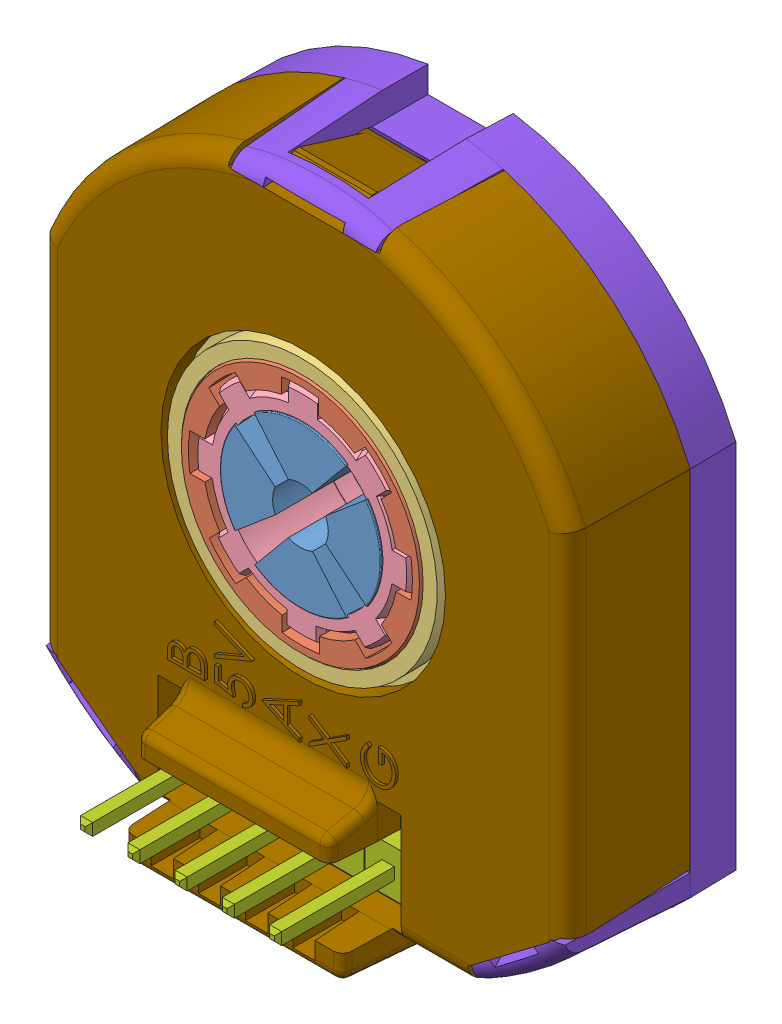
SolidWorks assembly CUI_DEVICES_CUI_DEVICES_AMT103-D0048-I3000-S, configuration Default. Lengths in mm.
Overall size (36.33 37.04 14.49).
9 component instances, 9 part files, 0 mates.
Components (placement in the parent):
- CUI_DEVICES_AMT-Sleeve-REV-D(3 mm)-1: CUI_DEVICES_AMT-Sleeve-REV-D(3 mm) [Default] at (0 0 -2.42) x (0.999996 0.002864 0) z (0 0 1) size (10.79 10.79 7.8)
- CUI_DEVICES_AMT-Hub-Top-REV-D1-1: CUI_DEVICES_AMT-Hub-Top-REV-D1 [Default] at (0 0 2.13) x (0.999996 0.002864 0) z (0 0 1) size (14 14 5.67)
- CUI_DEVICES_AMT-Hub-Bottom-REV-B-1: CUI_DEVICES_AMT-Hub-Bottom-REV-B [Default] at (0 0 2.43) x (0.999998 -0.001942 0) z (0 0 1) size (17.3 17.3 3.2)
- CUI_DEVICES_AMT10X-Shaft-Adaptor-REV-E-1: CUI_DEVICES_AMT10X-Shaft-Adaptor-REV-E [Default] at (0 0 0.03) x (0.999996 0.002864 0) z (0 0 1) size (11.8 11.8 7.8)
- CUI_DEVICES_Receiver-board-1: CUI_DEVICES_Receiver-board [Default] at (72.2834 -20.351 3.03) x (-1 0 0) z (0 0 -1) size (26.5 26.62 0.41)
- CUI_DEVICES_Rotor-board-REV F-1: CUI_DEVICES_Rotor-board-REV F [Default] at (0 0 2.13) x (0.807874 -0.589355 0) z (0 0 1) size (26 26 0.3)
- CUI_DEVICES_Transmitter-board AMT10(AMT-103)-1: CUI_DEVICES_Transmitter-board AMT10(AMT-103) [Default] at (19.1596 -17.1102 1.22) x (-1 0 0) z (0 0 -1) size (26.63 29.61 12.1)
- CUI_DEVICES_AMT-103-Base-REV-K(Default)-1: CUI_DEVICES_AMT-103-Base-REV-K(Default) [Default] at (0 0 -1) x (-1 0 0) z (0 0 -1) size (28.59 34.62 9.11)
- CUI_DEVICES_AMT-103-Top-Cover-REV-I-1: CUI_DEVICES_AMT-103-Top-Cover-REV-I [Default] at (0 0 5.23) x (-1 0 0) z (0 0 -1) size (28.6 33.94 9.26)
